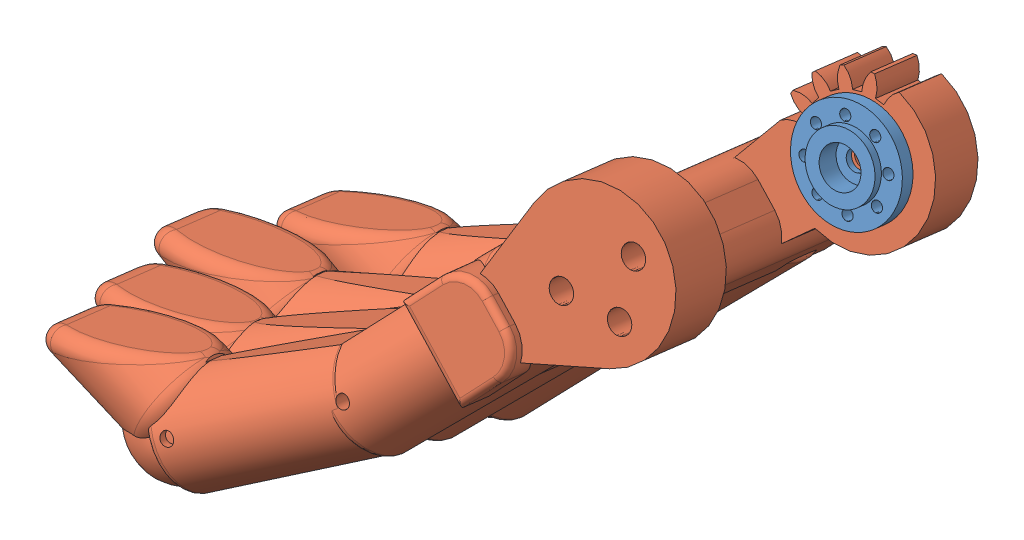
SolidWorks assembly finger2, configuration ﾃﾞﾌｫﾙﾄ. Lengths in mm.
Overall size (105.91 89.47 93.92).
2 component instances, 2 part files, 2 mates.
Components (placement in the parent):
- SmallHornB-4: SmallHornB [ﾃﾞﾌｫﾙﾄ] at (-117.6729 45.8179 117.3222) x (0.528861 0.812287 -0.24596) z (-0.114962 -0.218571 -0.969026) size (16 16 4.2)
- 4fingerAsm2-1: 4fingerAsm2 [ﾃﾞﾌｫﾙﾄ] at (-167.6263 120.9697 83.3879) x (-0.036835 -0.973884 0.224037) z (-0.114962 -0.218571 -0.969026) size (70.01 95.94 70.45)
Mates (geometry in assembly coordinates):
- 一致55: coincident anti-aligned: plane of SmallHornB-4 through (-118.0408 45.1185 114.2214) normal (-0.114962 -0.218571 -0.969026); plane of 4fingerAsm2-1 through (-118.0408 45.1185 114.2214) normal (0.114962 0.218571 0.969026)
- 同心円68: concentric aligned: circle of SmallHornB-4; cylinder of 4fingerAsm2-1 through (-116.7402 47.5913 125.1846) axis (-0.114962 -0.218571 -0.969026) radius 1.5
